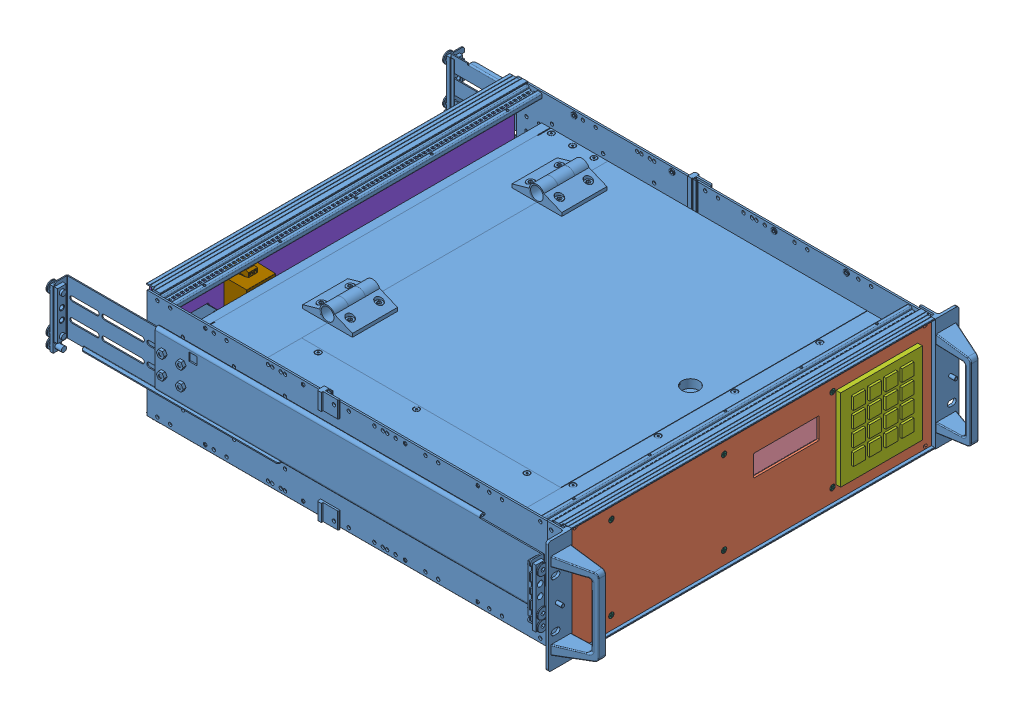
SolidWorks assembly MLA-0387-M6, configuration Default. Lengths in mm.
Overall size (632.74 133.75 484.52).
38 component instances, 13 part files, 6 mates.
Components (placement in the parent):
- HSB COMBI-1: HSB COMBI [Default] at (126.8815 474.9084 703.8365) size (632.74 133.75 484.52)
- MLA-0387-M5-1: MLA-0387-M5 [Default] at (292.9876 641.3112 670.6339) x (0 0 -1) z (0 -1 0) size (426.52 64.16 128.7)
  - MLA-0387-M1-1: MLA-0387-M1 [Default] at (-31.2027 -157.9839 598.0559) size (426.52 2.5 128.7)
  - MLA-0387-P1-PA1-1: MLA-0387-P1-PA1 [Default] at (-3.4827 205.6061 369.0559) x (1 0 0) z (0 1 0) size (300 107.5 53.66)
  - WH2004A1-YYH-1: WH2004A1-YYH [Default] at (178.2672 208.6161 325.5559) x (1 0 0.000001) z (0 1 0) size (98 60 10.6)
  - pan_head_phillip_M2x4-1: pan_head_phillip_M2x4 [Default] at (180.7673 210.2161 268.0559) x (1 0 0) z (0 0 1) size (4 9.78 4)
  - pan_head_phillip_M2x4-2: pan_head_phillip_M2x4 [Default] at (273.7673 210.2161 268.0559) x (1 0 0) z (0 0 1) size (4 9.78 4)
  - pan_head_phillip_M2x4-3: pan_head_phillip_M2x4 [Default] at (273.7873 210.2161 323.0559) x (1 0 0) z (0 0 1) size (4 9.78 4)
  - pan_head_phillip_M2x4-4: pan_head_phillip_M2x4 [Default] at (180.7673 210.2161 323.0559) x (1 0 0) z (0 0 1) size (4 9.78 4)
  - SCREW_ISO 7046-1: SCREW_ISO 7046 [VIJAK M 3x 10] at (21.5173 222.1161 266.5559) x (0 -1 0) z (0 0 1) size (10 5.6 5.6)
  - SCREW_ISO 7046-2: SCREW_ISO 7046 [VIJAK M 3x 10] at (21.5173 222.1161 364.0559) x (0 -1 0) z (1 0 0) size (10 5.6 5.6)
  - SCREW_ISO 7046-3: SCREW_ISO 7046 [VIJAK M 3x 10] at (154.0173 222.1161 364.0559) x (0 -1 0) z (0 0 1) size (10 5.6 5.6)
  - SCREW_ISO 7046-4: SCREW_ISO 7046 [VIJAK M 3x 10] at (154.0173 222.1161 266.5559) x (0 -1 0) z (0 0 1) size (10 5.6 5.6)
  - SCREW_ISO 7046-5: SCREW_ISO 7046 [VIJAK M 3x 10] at (281.5173 222.1161 266.5559) x (0 -1 0) z (0 0 1) size (10 5.6 5.6)
  - SCREW_ISO 7046-6: SCREW_ISO 7046 [VIJAK M 3x 10] at (281.5173 221.9757 364.0559) x (0 -1 0) z (-0.743067 0 0.669217) size (10 5.6 5.6)
  - Storm_7016010-2: Storm_7016010 [Default] at (285.6073 222.1161 363.1059) x (1 0 0) z (0 1 0) size (96 96 22)
- MLA-0387-M2-1: MLA-0387-M2 [Default] at (227.9738 628.7269 255.9596) x (0 0 1) z (0 -1 0) size (426.52 36.95 128.7)
  - MLA-0387-M3-1: MLA-0387-M3 [Default] at (14.077 -174.6299 585.4715) size (426.52 2.5 128.7)
  - ECL15US12-S-1: ECL15US12-S [Default] at (340.987 202.9701 302.5215) x (0 0 -1) z (1 0 0) size (84 26.49 34.5)
  - DC11_0001_001-1: DC11_0001_001 [Default] at (389.437 205.4701 308.5715) x (1 0 0) z (0 1 0) size (44 34 36.95)
  - SCREW_ISO 7046-1: SCREW_ISO 7046 [VIJAK M 3x 10] at (371.437 207.6701 302.5215) x (0 -1 0) z (0 0 1) size (10 5.6 5.6)
  - SCREW_ISO 7046-2: SCREW_ISO 7046 [VIJAK M 3x 10] at (407.437 207.6701 302.5215) x (0 -1 0) z (0 0 1) size (10 5.6 5.6)
  - M3 X 10mm Screw-1: M3 X 10mm Screw [Default] at (328.287 207.8701 340.0215) x (0 -1 0) z (0 0 1) size (12.61 5.6 5.6)
  - M3 X 10mm Screw-2: M3 X 10mm Screw [Default] at (353.687 207.8701 340.2611) x (0 -1 0) z (0 0 1) size (12.61 5.6 5.6)
  - M3 X 10mm Screw-3: M3 X 10mm Screw [Default] at (353.687 207.8701 265.0215) x (0 -1 0) z (0 0 1) size (12.61 5.6 5.6)
  - M3 X 10mm Screw-4: M3 X 10mm Screw [Default] at (328.287 207.8701 265.0215) x (0 -1 0) z (0 0 1) size (12.61 5.6 5.6)
  - M3 screw size FLAT WASHER-1: M3 screw size FLAT WASHER [Default] at (407.437 202.9701 302.5215) x (0.944963 0 -0.327176) z (0 -1 0) size (7 7 0.6)
  - M3 screw size FLAT WASHER-2: M3 screw size FLAT WASHER [Default] at (371.437 202.3701 302.5215) x (1 0 0) z (0 1 0) size (7 7 0.6)
  - M3 x 0.5mm Thread HEX NUT-1: M3 x 0.5mm Thread HEX NUT [Default] at (407.4348 201.1701 302.5562) x (1 0 0) z (0 1 0) size (5.5 6.35 2.6)
  - M3 x 0.5mm Thread HEX NUT-2: M3 x 0.5mm Thread HEX NUT [Default] at (371.4463 201.1701 302.55) x (1 0 0) z (0 1 0) size (5.5 6.35 2.6)
  - M3 screw size FLAT WASHER-3: M3 screw size FLAT WASHER [Default] at (353.687 199.8701 340.2611) x (1 0 0) z (0 1 0) size (7 7 0.6)
  - M3 screw size FLAT WASHER-4: M3 screw size FLAT WASHER [Default] at (328.287 199.8701 340.0215) x (1 0 0) z (0 1 0) size (7 7 0.6)
  - M3 screw size FLAT WASHER-5: M3 screw size FLAT WASHER [Default] at (328.287 200.4701 265.0215) x (1 0 0) z (0 -1 0) size (7 7 0.6)
  - M3 screw size FLAT WASHER-6: M3 screw size FLAT WASHER [Default] at (353.687 200.4701 265.0215) x (1 0 0) z (0 -1 0) size (7 7 0.6)
  - M3 x 0.5mm Thread HEX NUT-3: M3 x 0.5mm Thread HEX NUT [Default] at (328.3059 198.6701 265.0157) x (1 0 0) z (0 -1 0) size (5.5 6.35 2.6)
  - M3 x 0.5mm Thread HEX NUT-4: M3 x 0.5mm Thread HEX NUT [Default] at (353.679 198.6701 264.9262) x (1 0 0) z (0 -1 0) size (5.5 6.35 2.6)
  - M3 x 0.5mm Thread HEX NUT-5: M3 x 0.5mm Thread HEX NUT [Default] at (353.654 198.6701 340.285) x (1 0 0) z (0 1 0) size (5.5 6.35 2.6)
  - M3 x 0.5mm Thread HEX NUT-6: M3 x 0.5mm Thread HEX NUT [Default] at (328.2745 198.6701 340.0301) x (1 0 0) z (0 1 0) size (5.5 6.35 2.6)
Mates (geometry in assembly coordinates):
- Parallel1: parallel anti-aligned: plane of HSB COMBI-1 through (518.1037 390.9554 270.0365) normal (0 -1 0); plane of MLA-0387-M5-1/MLA-0387-M1-1 through (512.6037 390.5554 699.1965) normal (0 1 0)
- Concentric1: concentric anti-aligned: cylinder of HSB COMBI-1 through (507.9037 387.4554 691.6765) axis (1 0 0) radius 0.974; cylinder of MLA-0387-M5-1/MLA-0387-M1-1 through (512.6037 387.4554 691.6765) axis (-1 0 0) radius 1.8
- Coincident3: coincident anti-aligned: plane of HSB COMBI-1 through (25.0037 381.4554 270.0365) normal (-1 0 0); plane of MLA-0387-M2-1/MLA-0387-M3-1 through (25.0037 346.3312 278.1169) normal (1 0 0)
- Parallel2: parallel anti-aligned: plane of HSB COMBI-1 through (19.5037 390.9554 701.8365) normal (0 -1 0); plane of MLA-0387-M2-1/MLA-0387-M3-1 through (25.0037 390.5554 272.6765) normal (0 1 0)
- Concentric2: concentric aligned: cylinder of HSB COMBI-1 through (29.7037 387.4554 280.1965) axis (1 0 0) radius 0.974; cylinder of MLA-0387-M2-1/MLA-0387-M3-1 through (25.0037 387.4554 280.1965) axis (1 0 0) radius 1.8
- Coincident4: coincident anti-aligned: plane of HSB COMBI-1 through (512.6037 270.9554 270.0365) normal (1 0 0); plane of MLA-0387-M5-1/MLA-0387-M1-1 through (512.6037 346.3312 693.7562) normal (-1 0 0)
